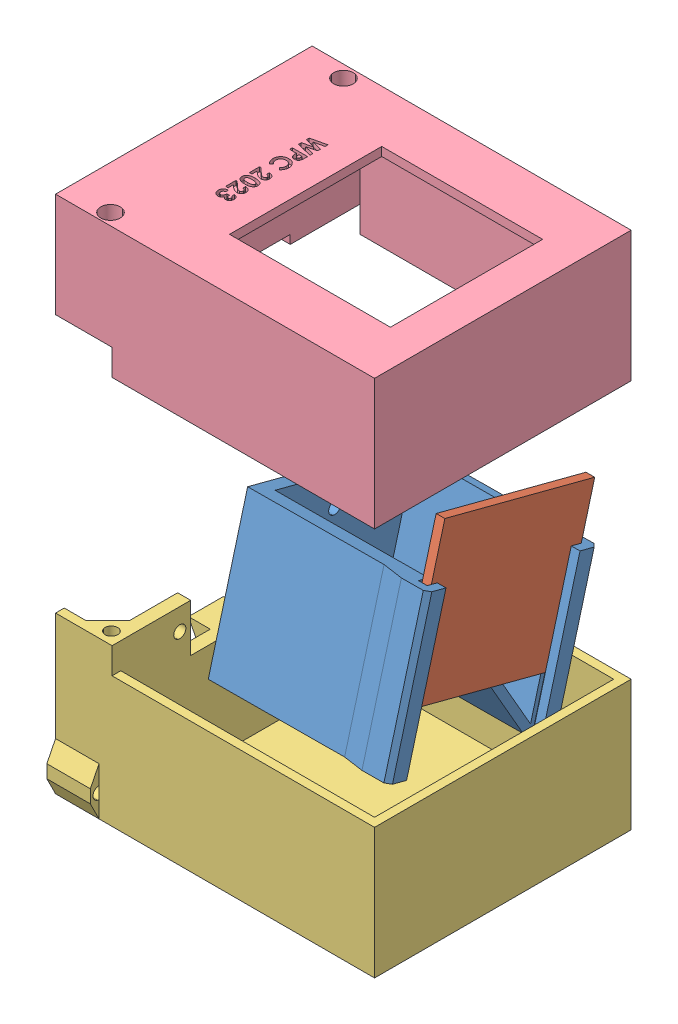
SolidWorks assembly tugas_WPC, configuration Default. Lengths in mm.
Overall size (73.35 119.41 63).
4 component instances, 4 part files, 4 mates.
Components (placement in the parent):
- Kotak_dalam_Part1-1: Kotak_dalam_Part1 [Default] at (58.5102 4.3143 24.1062) x (-0.008727 -0.258809 -0.965889) z (0 -0.965926 0.258819) size (41 42 35)
- Kotak_dalam_Part2-1: Kotak_dalam_Part2 [Default] at (96.8142 58.6789 45.4292) x (-0.008727 -0.258809 -0.965889) z (0 -0.965926 0.258819) size (36 2 35)
- Pembungkus_Part1-1: Pembungkus_Part1 [Default] at (34.6586 -16.8945 12.4299) size (73.35 36 63)
- Pembungkus_Part2-1: Pembungkus_Part2 [Default] at (34.6586 102.5182 67.4299) x (1 0 0) z (0 0 -1) size (73.35 30 59)
Mates (geometry in assembly coordinates):
- Coincident1: coincident anti-aligned: plane of Kotak_dalam_Part1-1 through (98.4999 3.9651 22.8031) normal (0.008727 0.258809 0.965889); plane of Kotak_dalam_Part2-1 through (98.4999 49.3573 10.6404) normal (-0.008727 -0.258809 -0.965889)
- Coincident2: coincident anti-aligned: plane of Kotak_dalam_Part1-1 through (96.5087 4.2285 23.7859) normal (0.999962 -0.002259 -0.008429); plane of Kotak_dalam_Part2-1 through (96.8142 58.6789 45.4292) normal (-0.999962 0.002259 0.008429)
- Coincident3: coincident aligned: plane of Pembungkus_Part1-1 through (104.6586 13.1055 12.4299) normal (0 0 1); plane of Pembungkus_Part2-1 through (33.3084 72.5182 12.4299) normal (0 0 1)
- Coincident4: coincident aligned: plane of Pembungkus_Part1-1 through (104.6586 13.1055 67.4299) normal (-1 0 0); plane of Pembungkus_Part2-1 through (104.6586 72.5182 12.4299) normal (-1 0 0)
